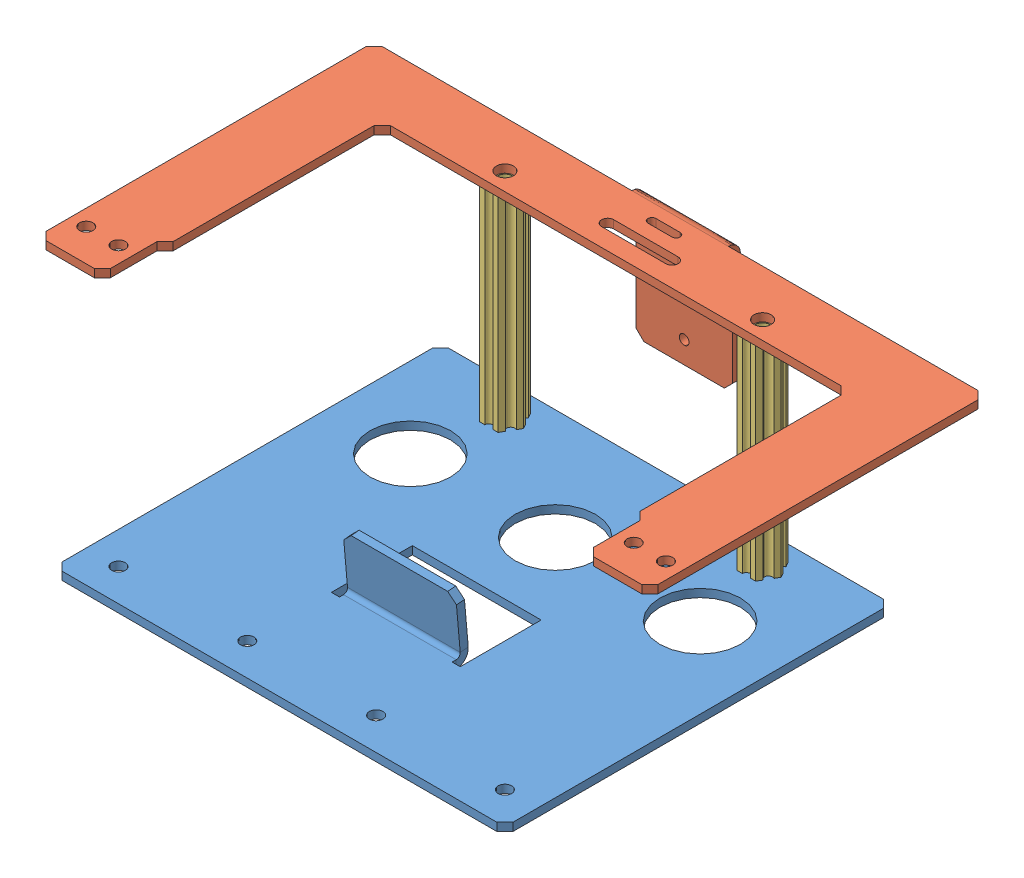
SolidWorks assembly BatBox, configuration Default. Lengths in mm.
Overall size (241.3 93.09 162.75).
6 component instances, 4 part files, 12 mates.
Components (placement in the parent):
- am-3959 AM14U4 Vertical Battery Mount Floor Plate-1: am-3959 AM14U4 Vertical Battery Mount Floor Plate [Default] at (-22.9363 77.673 216.7192) size (177.8 25.3 152.4)
- am-3958 AM14U4 Vertical Battery Mount C Plate-1: am-3958 AM14U4 Vertical Battery Mount C Plate [Default] at (-54.6863 158.826 191.3192) size (241.3 50.8 137.35)
- am-churro 3_385 churro tube-1: am-churro 3_385 churro tube [Default] at (15.1637 158.826 77.0192) x (1 0 0) z (0 -1 0) size (14.66 12.7 81.15)
- am-churro 3_385 churro tube-2: am-churro 3_385 churro tube [Default] at (116.7637 158.826 77.0192) x (1 0 0) z (0 -1 0) size (14.66 12.7 81.15)
- FHTS 0.25-20-0.75-3: FHTS 0.25-20-0.75 [FHTS 0.25-20-G-0.75-C] at (116.7637 74.498 77.0192) x (0 1 0) z (0 0 1) size (24.64 12.19 12.19)
- FHTS 0.25-20-0.75-4: FHTS 0.25-20-0.75 [FHTS 0.25-20-G-0.75-C] at (15.1637 74.498 77.0192) x (0 1 0) z (0 0 1) size (24.64 12.19 12.19)
Mates (geometry in assembly coordinates):
- Concentric1: concentric anti-aligned: cylinder of am-3959 AM14U4 Vertical Battery Mount Floor Plate-1 through (116.7637 74.498 77.0192) axis (0 1 0) radius 3.3782; cylinder of am-3958 AM14U4 Vertical Battery Mount C Plate-1 through (116.7637 162.001 77.0192) axis (0 -1 0) radius 3.3782
- Concentric2: concentric anti-aligned: cylinder of am-3959 AM14U4 Vertical Battery Mount Floor Plate-1 through (15.1637 74.498 77.0192) axis (0 1 0) radius 3.3782; cylinder of am-3958 AM14U4 Vertical Battery Mount C Plate-1 through (15.1637 162.001 77.0192) axis (0 -1 0) radius 3.3782
- Concentric3: concentric aligned: cylinder of am-3959 AM14U4 Vertical Battery Mount Floor Plate-1 through (116.7637 74.498 77.0192) axis (0 1 0) radius 3.3782; cylinder of am-churro 3_385 churro tube-2 through (116.7637 -145.974 77.0192) axis (0 1 0) radius 2.9337
- Coincident1: coincident anti-aligned: plane of am-3958 AM14U4 Vertical Battery Mount C Plate-1 through (-54.6863 158.826 191.3192) normal (0 -1 0); plane of am-churro 3_385 churro tube-2 through (122.2629 158.826 80.1942) normal (0 1 0)
- Coincident2: coincident anti-aligned: plane of am-3959 AM14U4 Vertical Battery Mount Floor Plate-1 through (-22.9363 77.673 216.7192) normal (0 1 0); plane of am-churro 3_385 churro tube-2 through (116.7637 77.673 77.0192) normal (0 -1 0)
- Concentric4: concentric anti-aligned: cylinder of am-3958 AM14U4 Vertical Battery Mount C Plate-1 through (15.1637 162.001 77.0192) axis (0 -1 0) radius 3.3782; cylinder of am-churro 3_385 churro tube-1 through (15.1637 -145.974 77.0192) axis (0 1 0) radius 2.9337
- Coincident3: coincident anti-aligned: plane of am-3958 AM14U4 Vertical Battery Mount C Plate-1 through (-54.6863 158.826 191.3192) normal (0 -1 0); plane of am-churro 3_385 churro tube-1 through (20.6629 158.826 80.1942) normal (0 1 0)
- Coincident4: coincident anti-aligned: plane of am-3959 AM14U4 Vertical Battery Mount Floor Plate-1 through (-22.9363 77.673 216.7192) normal (0 1 0); plane of am-churro 3_385 churro tube-1 through (15.1637 77.673 77.0192) normal (0 -1 0)
- Concentric71: concentric anti-aligned: cylinder of am-3959 AM14U4 Vertical Battery Mount Floor Plate-1 through (116.7637 74.498 77.0192) axis (0 1 0) radius 3.3782; cylinder of FHTS 0.25-20-0.75-3 through (116.7637 74.498 77.0192) axis (0 -1 0) radius 3.175
- Coincident71: coincident anti-aligned: plane of am-3959 AM14U4 Vertical Battery Mount Floor Plate-1 through (-22.9363 74.498 216.7192) normal (0 -1 0); plane of FHTS 0.25-20-0.75-3 through (113.5887 74.498 77.0192) normal (0 1 0)
- Concentric81: concentric anti-aligned: cylinder of am-3959 AM14U4 Vertical Battery Mount Floor Plate-1 through (15.1637 74.498 77.0192) axis (0 1 0) radius 3.3782; cylinder of FHTS 0.25-20-0.75-4 through (15.1637 74.498 77.0192) axis (0 -1 0) radius 3.175
- Coincident81: coincident anti-aligned: plane of am-3959 AM14U4 Vertical Battery Mount Floor Plate-1 through (-22.9363 74.498 216.7192) normal (0 -1 0); plane of FHTS 0.25-20-0.75-4 through (11.9887 74.498 77.0192) normal (0 1 0)
